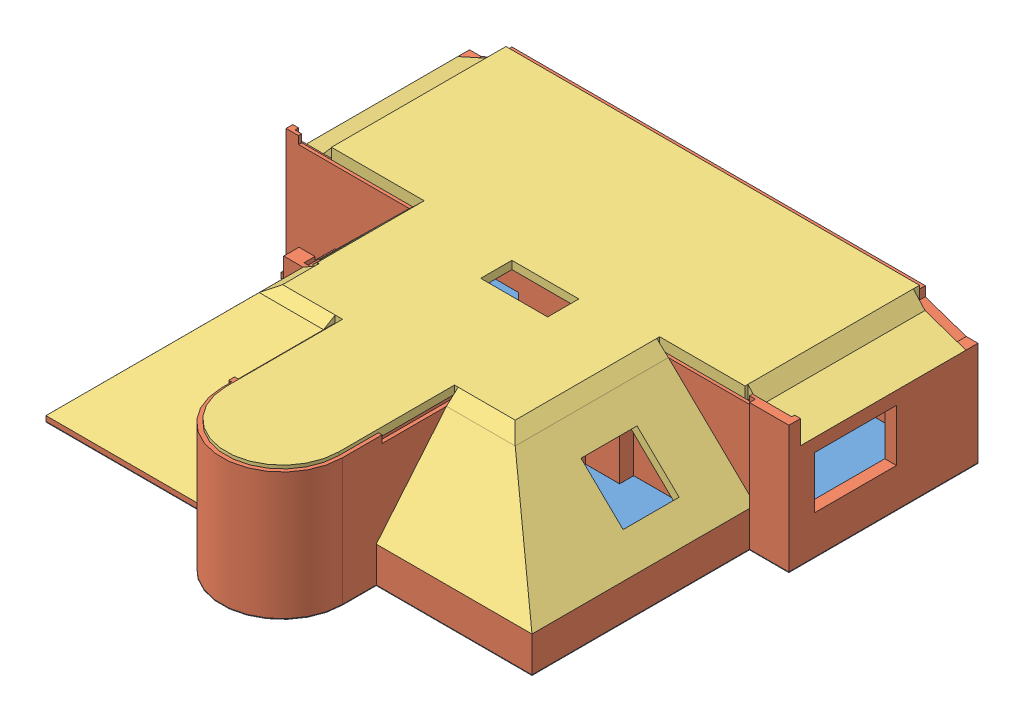
SolidWorks assembly Wohnung, configuration Standard. Lengths in mm.
Overall size (10002 2575 9850.5).
9 component instances, 8 part files, 23 mates.
Components (placement in the parent):
- Grundplatte-1: Grundplatte [Standard] at (1350.1892 -405.6037 9609) size (10002 11 9850.5)
- Wände-1: Wände [Standard] at (-2233.0009 -405.6037 7940.1019) size (10002 2500 9850.5)
- Decke-1: Decke [Standard] at (291.8994 2000.3963 -523.8606) size (10002 2464 9655.75)
- Deckenplatte-2: Deckenplatte [Standard] at (1266.1892 2159.3963 7589) size (4039 2 6110) (hidden)
- Decke Wand-1: Decke Wand [Standard] at (727.0307 2160.3963 1192.1442) size (4039.01 2240 6110) (hidden)
- Magnat-Box-1: Magnat-Box [Standard] at (595.2241 -406.6037 7188.7977) x (0.173648 0 -0.984808) z (0.984808 0 0.173648) size (250 855 220)
- Magnat-Box-2: Magnat-Box [Standard] at (5009.1543 -406.6037 7188.7977) x (-0.173648 0 -0.984808) z (0.984808 0 -0.173648) size (250 855 220)
- Wohnzimmer-Kommode-1: Wohnzimmer-Kommode [Standard] at (2802.1892 -406.6037 7081) size (4000 1900 600)
- Panasonic-Tv-1: Panasonic-Tv [Standard] at (2690.6932 93.3963 7131) size (930 670 300)
Mates (geometry in assembly coordinates):
- Deckungsgleich3: coincident anti-aligned: plane of Grundplatte-1 through (1350.1892 -405.6037 9609) normal (0 1 0); plane of Wände-1 through (391.6892 -405.6037 12550) normal (0 -1 0)
- Deckungsgleich4: coincident aligned: line of Grundplatte-1 through (1437.1892 -405.6037 9472) axis (0 0 -1); line of Wände-1 through (1437.1892 -405.6037 9472) axis (0 0 -1)
- Deckungsgleich5: coincident anti-aligned: line of Grundplatte-1 through (1437.1892 -405.6037 9472) axis (-1 0 0); line of Wände-1 through (1212.1892 -405.6037 9472) axis (1 0 0)
- Deckungsgleich6: coincident anti-aligned: plane of Wände-1 through (-2233.0009 2000.3963 7940.1019) normal (0 1 0); plane of Decke-1 through (291.8994 2000.3963 -523.8606) normal (0 -1 0)
- Deckungsgleich7: coincident aligned: plane of Wände-1 through (-909.3108 5433.3963 7437.5) normal (-1 0 0); line of Decke-1 through (-909.3108 2000.3963 7437.5) axis (0 0 1)
- Deckungsgleich9: coincident anti-aligned: plane of Wände-1 through (1509.6892 2150.3963 9540.5) normal (0 0 -1); plane of Decke-1 through (-909.3108 2158.3963 9540.5) normal (0 0 1)
- Deckungsgleich15: coincident anti-aligned: line of Decke-1 through (1266.1892 2158.3963 7589) axis (-1 0 0); line of Deckenplatte-2 through (-50.8108 2158.3963 7589) axis (1 0 0)
- Deckungsgleich16: coincident anti-aligned: line of Decke-1 through (1266.1892 2158.3963 8203) axis (0 0 -1); line of Deckenplatte-2 through (1266.1892 2158.3963 7589) axis (0 0 1)
- Deckungsgleich17: coincident aligned: line of Deckenplatte-2 through (-1647.8108 2160.3963 3980) axis (0 0 1); line of Decke Wand-1 through (-1647.8108 2160.3963 3980) axis (0 0 1)
- Deckungsgleich18: coincident aligned: line of Deckenplatte-2 through (-1647.8108 2160.3963 10090) axis (1 0 0); line of Decke Wand-1 through (-1647.8108 2160.3963 10090) axis (1 0 0)
- Deckungsgleich19: coincident anti-aligned: plane of Grundplatte-1 through (391.6892 -406.6037 12550) normal (0 1 0); plane of Magnat-Box-1 through (595.2241 -406.6037 7188.7977) normal (0 -1 0)
- Deckungsgleich20: coincident anti-aligned: plane of Grundplatte-1 through (391.6892 -406.6037 12550) normal (0 1 0); plane of Magnat-Box-2 through (5009.1543 -406.6037 7188.7977) normal (0 -1 0)
- Winkel1: planar angle = 0.174533 rad anti-aligned: plane of Magnat-Box-2 through (5139.1892 448.3963 7292.7974) normal (0.173648 0 0.984808); plane of Wände-1 through (415.1892 2094.3963 7381) normal (0 0 -1)
- Abstand2: distance = 50 mm: line of Magnat-Box-2 through (4922.5315 448.3963 7331) axis (0 -1 0); plane of Wände-1 through (415.1892 2094.3963 7381) normal (0 0 -1)
- Abstand3: distance = 50 mm: line of Magnat-Box-2 through (5139.1892 448.3963 7292.7974) axis (0 -1 0); plane of Wände-1 through (5189.1892 2094.3963 7381) normal (-1 0 0)
- Winkel2: planar angle = 0.174533 rad anti-aligned: plane of Wände-1 through (415.1892 2094.3963 7381) normal (0 0 -1); plane of Magnat-Box-1 through (681.8469 448.3963 7331) normal (-0.173648 0 0.984808)
- Abstand4: distance = 50 mm: line of Magnat-Box-1 through (681.8469 448.3963 7331) axis (0 -1 0); plane of Wände-1 through (415.1892 2094.3963 7381) normal (0 0 -1)
- Abstand5: distance = 50 mm: plane of Wände-1 through (415.1892 2094.3963 6505) normal (1 0 0); line of Magnat-Box-1 through (465.1892 448.3963 7292.7974) axis (0 -1 0)
- Deckungsgleich27: coincident anti-aligned: plane of Grundplatte-1 through (391.6892 -406.6037 12550) normal (0 1 0); plane of Wohnzimmer-Kommode-1 through (2802.1892 -406.6037 7081) normal (0 -1 0)
- Deckungsgleich28: coincident anti-aligned: plane of Wände-1 through (415.1892 2094.3963 7381) normal (0 0 -1); plane of Wohnzimmer-Kommode-1 through (802.1892 93.3963 7381) normal (0 0 1)
- Deckungsgleich29: coincident anti-aligned: plane of Wohnzimmer-Kommode-1 through (2802.1892 93.3963 7081) normal (0 1 0); plane of Panasonic-Tv-1 through (2690.6932 93.3963 7131) normal (0 -1 0)
- Abstand6: distance = 100 mm anti-aligned: plane of Panasonic-Tv-1 through (2490.6932 133.3963 7281) normal (0 0 1); plane of Wände-1 through (415.1892 2094.3963 7381) normal (0 0 -1)
- Abstand7: distance = 387 mm anti-aligned: plane of Wände-1 through (5189.1892 2094.3963 7381) normal (-1 0 0); plane of Wohnzimmer-Kommode-1 through (4802.1892 93.3963 7381) normal (1 0 0)
